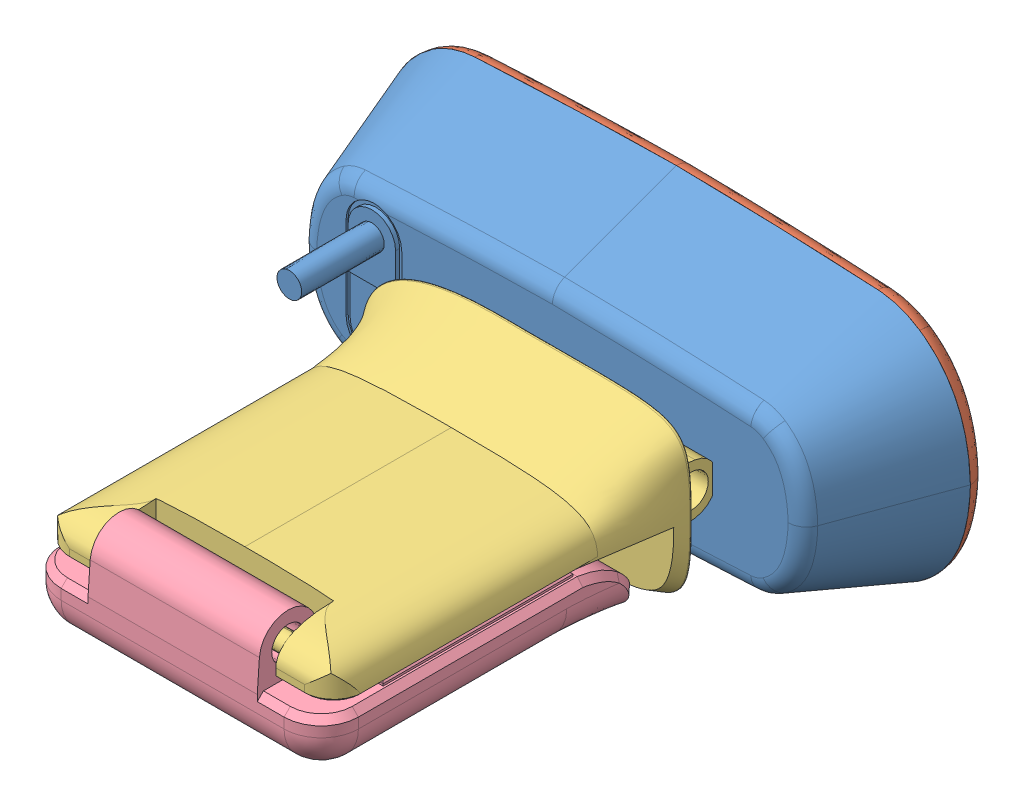
SolidWorks assembly c310, configuration Défaut. Lengths in mm.
Overall size (71.5 31.65 69.48).
4 component instances, 4 part files, 9 mates.
Components (placement in the parent):
- c310-corps-1: c310-corps [Default] at (1.7129 6.6622 61.3001) size (71.27 31.35 30.56)
- c310-cache-1: c310-cache [Default] at (1.7129 6.6622 59.0501) x (-1 0 0) z (0 0 -1) size (71.5 31.65 2.5)
- clip-1-1: clip-1 [Default] at (4.1303 6.6622 81.7235) x (-1 0 0) z (0 0 1) size (43.19 23.62 48.27)
- clip-2-1: clip-2 [Default] at (4.8803 2.4122 105.5985) x (-1 0 0) z (0 0 -1) size (36 14.88 39.47)
Mates (geometry in assembly coordinates):
- Coaxiale1: concentric anti-aligned: cylinder of c310-corps-1 through (18.3379 6.6622 58.3001) axis (0 0 1) radius 12.125; cylinder of c310-cache-1 through (18.3379 6.6622 61.3001) axis (0 0 -1) radius 12.325
- Coïncidente2: coincident anti-aligned: plane of c310-corps-1 through (33.6284 -4.3557 61.3001) normal (0 0 -1); plane of c310-cache-1 through (35.7028 -1.1709 61.3001) normal (0 0 1)
- Coïncidente3: coincident anti-aligned: circle of c310-corps-1; circle of c310-cache-1
- Coaxiale2: concentric aligned: cylinder of c310-corps-1 through (-4.6629 6.6622 78.7985) axis (1 0 0) radius 2.2984; cylinder of clip-1-1 through (-17.558 6.6622 78.7985) axis (1 0 0) radius 2
- Distance2: distance = 0.25 mm anti-aligned: plane of c310-corps-1 through (8.8379 3.3122 81.3001) normal (1 0 0); plane of clip-1-1 through (9.0879 10.1622 75.7235) normal (-1 0 0)
- Coaxiale3: concentric: cylinder of clip-1-1 through (18.8617 9.1622 121.7235) axis (-1 0 0) radius 1.1425; cylinder of clip-2-1 through (22.8806 9.1622 121.7235) axis (-1 0 0) radius 2
- Distance3: distance = 0.5 mm: plane of clip-2-1 through (-5.3697 12.6622 111.7283) normal (-1 0 0); plane of clip-1-1 through (-5.8697 18.4571 81.7235) normal (1 0 0)
- Parallèle1: parallel anti-aligned: plane of c310-corps-1 through (-27.2756 1.1177 76.3001) normal (0 0 1); plane of clip-1-1 through (21.3869 15.7597 81.7235) normal (0 0 -1)
- Parallèle2: parallel anti-aligned: plane of clip-1-1 through (4.1303 6.9122 81.7235) normal (0 -1 0); plane of clip-2-1 through (4.8803 6.6622 105.5985) normal (0 1 0)
